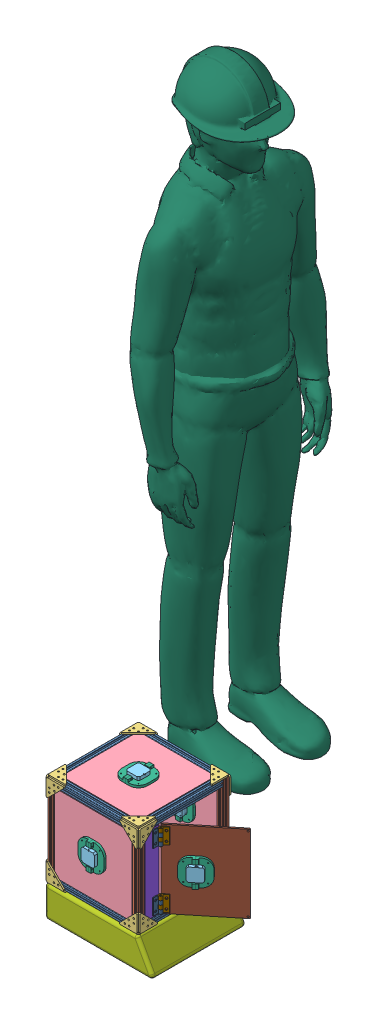
SolidWorks assembly boxOfDreams, configuration Default. Lengths in mm.
Overall size (790.39 1899.73 1088.72).
82 component instances, 15 part files, 239 mates.
Components (placement in the parent):
- 2020alu-1: 2020alu [Default] at origin size (20 20 250)
- 2020alu-2: 2020alu [Default] at (10 0 260) x (0 0 1) z (1 0 0) size (20 20 250)
- 2020alu-3: 2020alu [Default] at (270 0 0) size (20 20 250)
- 2020alu-4: 2020alu [Default] at (10 0 -10) x (0 0 -1) z (1 0 0) size (20 20 250)
- 2020alu_290-1: 2020alu_290 [Default] at (0 280 260) x (1 0 0) z (0 -1 0) size (20 20 290)
- 2020alu_290-2: 2020alu_290 [Default] at (270 280 260) x (0 0 1) z (0 -1 0) size (20 20 290)
- 2020alu_290-3: 2020alu_290 [Default] at (270 280 -10) x (1 0 0) z (0 -1 0) size (20 20 290)
- 2020alu_290-4: 2020alu_290 [Default] at (0 -10 -10) x (0 0 1) z (0 1 0) size (20 20 290)
- 2020alu-6: 2020alu [Default] at (260 270 260) x (0 0 1) z (-1 0 0) size (20 20 250)
- 2020alu-7: 2020alu [Default] at (270 270 0) size (20 20 250)
- 2020alu-8: 2020alu [Default] at (10 270 -10) x (0 0 -1) z (1 0 0) size (20 20 250)
- 2020alu-9: 2020alu [Default] at (0 270 0) size (20 20 250)
- bracket-2: bracket [Default] at (20 250 -20) x (-1 0 0) z (0 0 -1) size (55.76 55.76 5)
- bracket-3: bracket [Default] at (-15 250 10) x (0 0 -1) z (1 0 0) size (55.76 55.76 5)
- bracket-4: bracket [Default] at (20 285 10) x (-1 0 0) z (0 -1 0) size (55.76 55.76 5)
- bracket-5: bracket [Default] at (250 250 -25) size (55.76 55.76 5)
- bracket-7: bracket [Default] at (250 280 10) x (1 0 0) z (0 1 0) size (55.76 55.76 5)
- bracket-8: bracket [Default] at (250 20 -25) x (0 -1 0) z (0 0 1) size (55.76 55.76 5)
- bracket-10: bracket [Default] at (20 20 -20) x (0 -1 0) z (0 0 -1) size (55.76 55.76 5)
- glassPlex-2: glassPlex [Default] at (135.0355 135.0355 -20) size (247 247 5)
- bracket-11: bracket [Default] at (20 285 240) x (0 0 1) z (0 -1 0) size (55.76 55.76 5)
- bracket-12: bracket [Default] at (250 280 240) x (0 0 1) z (0 1 0) size (55.76 55.76 5)
- bracket-13: bracket [Default] at (20 250 275) x (-1 0 0) z (0 0 -1) size (55.76 55.76 5)
- glassPlex-3: glassPlex [Default] at (135.0355 280 124.9645) x (1 0 0) z (0 -1 0) size (247 247 5)
- bracket-14: bracket [Default] at (250 250 270) size (55.76 55.76 5)
- bracket-15: bracket [Default] at (250 20 270) x (0 -1 0) z (0 0 1) size (55.76 55.76 5)
- bracket-16: bracket [Default] at (20 20 270) x (-1 0 0) z (0 0 1) size (55.76 55.76 5)
- glassPlex-4: glassPlex [Default] at (134.9645 135.0355 265) size (247 247 5)
- bracket-17: bracket [Default] at (-10 250 240) x (0 0 1) z (-1 0 0) size (55.76 55.76 5)
- bracket-18: bracket [Default] at (-10 20 240) x (0 -1 0) z (-1 0 0) size (55.76 55.76 5)
- bracket-19: bracket [Default] at (-10 20 10) x (0 0 -1) z (-1 0 0) size (55.76 55.76 5)
- glassPlex-5: glassPlex [Default] at (-10 135.0355 125.0355) x (0 0 -1) z (1 0 0) size (247 247 5)
- bracket-22: bracket [Default] at (250 -15 10) x (1 0 0) z (0 1 0) size (55.76 55.76 5)
- bracket-23: bracket [Default] at (250 -10 240) x (1 0 0) z (0 -1 0) size (55.76 55.76 5)
- bracket-24: bracket [Default] at (20 -10 10) x (-1 0 0) z (0 -1 0) size (55.76 55.76 5)
- bracket-25: bracket [Default] at (20 -10 240) x (0 0 1) z (0 -1 0) size (55.76 55.76 5)
- glassPlex-6: glassPlex [Default] at (135.0355 -5 124.9645) x (1 0 0) z (0 -1 0) size (247 247 5)
- nema17-1: nema17 [Default] at (134.9645 135.0355 287) x (0 0 -1) z (1 0 0) size (77.9 47.49 42.3)
- nemaLock-1: nemaLock [Default] at (134.9645 135.0355 270) size (41.5 83 14.5)
- nemaLock-2: nemaLock [Default] at (134.9645 135.0355 270) x (-1 0 0) z (0 0 1) size (41.5 83 14.5)
- nemaLock-3: nemaLock [Default] at (134.9645 135.0355 265) x (1 0 0) z (0 0 -1) size (41.5 83 14.5)
- nemaLock-4: nemaLock [Default] at (134.9645 135.0355 265) x (-1 0 0) z (0 0 -1) size (41.5 83 14.5)
- nemaLock-5: nemaLock [Default] at (135.0355 -5 124.9645) x (0 0 -1) z (0 1 0) size (41.5 83 14.5)
- nemaLock-6: nemaLock [Default] at (135.0355 -5 124.9645) x (0 0 1) z (0 1 0) size (41.5 83 14.5)
- nemaLock-7: nemaLock [Default] at (135.0355 -10 124.9645) x (0 0 -1) z (0 -1 0) size (41.5 83 14.5)
- nemaLock-8: nemaLock [Default] at (135.0355 -10 124.9645) x (0 0 1) z (0 -1 0) size (41.5 83 14.5)
- nema17-2: nema17 [Default] at (135.0355 -27 124.9645) x (0 1 0) z (0 0 1) size (77.9 47.49 42.3)
- nemaLock-9: nemaLock [Default] at (135.0355 135.0355 -15) size (41.5 83 14.5)
- nemaLock-10: nemaLock [Default] at (135.0355 135.0355 -15) x (-1 0 0) z (0 0 1) size (41.5 83 14.5)
- nemaLock-11: nemaLock [Default] at (135.0355 135.0355 -20) x (-1 0 0) z (0 0 -1) size (41.5 83 14.5)
- nemaLock-12: nemaLock [Default] at (135.0355 135.0355 -20) x (1 0 0) z (0 0 -1) size (41.5 83 14.5)
- nema17-3: nema17 [Default] at (135.0355 135.0355 -37) x (0 0 1) z (-1 0 0) size (77.9 47.49 42.3)
- nemaLock-13: nemaLock [Default] at (135.0355 275 124.9645) x (-1 0 0) z (0 -1 0) size (41.5 83 14.5)
- nemaLock-14: nemaLock [Default] at (135.0355 275 124.9645) x (1 0 0) z (0 -1 0) size (41.5 83 14.5)
- nemaLock-15: nemaLock [Default] at (135.0355 280 124.9645) x (1 0 0) z (0 1 0) size (41.5 83 14.5)
- nemaLock-16: nemaLock [Default] at (135.0355 280 124.9645) x (-1 0 0) z (0 1 0) size (41.5 83 14.5)
- nema17-4: nema17 [Default] at (135.0355 297 124.9645) x (0 -1 0) z (0 0 1) size (77.9 47.49 42.3)
- nemaLock-17: nemaLock [Default] at (-5 135.0355 125.0355) x (0 0 -1) z (1 0 0) size (41.5 83 14.5)
- nemaLock-18: nemaLock [Default] at (-5 135.0355 125.0355) x (0 0 1) z (1 0 0) size (41.5 83 14.5)
- nemaLock-19: nemaLock [Default] at (-10 135.0355 125.0355) x (0 0 1) z (-1 0 0) size (41.5 83 14.5)
- nemaLock-20: nemaLock [Default] at (-10 135.0355 125.0355) x (0 0 -1) z (-1 0 0) size (41.5 83 14.5)
- nema17-5: nema17 [Default] at (-27 135.0355 125.0355) size (77.9 47.49 42.3)
- plateu-1: plateu [Default] at (160 -115 125) x (0 0 -1) z (0 1 0) size (300 343.09 100)
- bracket-26: bracket [Default] at (285 250 240) x (0 0 1) z (-1 0 0) size (55.76 55.76 5)
- bracket-27: bracket [Default] at (285 20 240) x (0 -1 0) z (-1 0 0) size (55.76 55.76 5)
- glassPlex_door1-1: glassPlex_door1 [Default] at (280 135.0355 125.0355) x (0 0 1) z (-1 0 0) size (43.5 247 5)
- Hinge A-1: Hinge A [Default] at (290.1769 228.5355 194.144) x (0.775881 0 -0.63088) z (0.63088 0 0.775881) size (26.5 50 11)
- Hinge B-1: Hinge B [Default] at (280 228.5355 215.5355) x (0 0 -1) z (1 0 0) size (26.5 50 11)
- Hinge A-2: Hinge A [Default] at (290.1769 41.5355 194.144) x (0.775881 0 -0.63088) z (0.63088 0 0.775881) size (26.5 50 11)
- Hinge B-2: Hinge B [Default] at (280 41.5355 215.5355) x (0 0 -1) z (1 0 0) size (26.5 50 11)
- glassPlex_door2-1: glassPlex_door2 [Default] at (344.1006 135.0355 150.2978) x (-0.775881 0 0.63088) z (-0.63088 0 -0.775881) size (203.5 247 5)
- nemaLock-21: nemaLock [Default] at (344.1006 135.0355 150.2978) x (0.775881 0 -0.63088) z (0.63088 0 0.775881) size (41.5 83 14.5)
- nemaLock-22: nemaLock [Default] at (344.1006 135.0355 150.2978) x (-0.775881 0 0.63088) z (0.63088 0 0.775881) size (41.5 83 14.5)
- nemaLock-23: nemaLock [Default] at (340.9462 135.0355 146.4184) x (-0.775881 0 0.63088) z (-0.63088 0 -0.775881) size (41.5 83 14.5)
- nemaLock-24: nemaLock [Default] at (340.9462 135.0355 146.4184) x (0.775881 0 -0.63088) z (-0.63088 0 -0.775881) size (41.5 83 14.5)
- nema17-6: nema17 [Default] at (354.8256 135.0355 163.4878) x (-0.63088 0 -0.775881) z (0.775881 0 -0.63088) size (77.9 47.49 42.3)
- camBracket-1: camBracket [Default] at (30.4289 265 20.4289) x (0.707107 0 -0.707107) z (0 1 0) size (77.78 38.89 10)
- Omnivision OV2710 CMOS CCTV Wide Angle USB Camera-1: Omnivision OV2710 CMOS CCTV Wide Angle USB Camera [Default] at (26.9289 260.0503 16.9289) x (-0.5 -0.707107 -0.5) z (-0.707107 0 0.707107) size (38 28 38)
- camBracket-2: camBracket [Default] at (239.5711 5 229.5711) x (0.707107 0 -0.707107) z (0 -1 0) size (77.78 38.89 10)
- Omnivision OV2710 CMOS CCTV Wide Angle USB Camera-2: Omnivision OV2710 CMOS CCTV Wide Angle USB Camera [Default] at (243.0711 9.9497 233.0711) x (0.5 0.707107 0.5) z (-0.707107 0 0.707107) size (38 28 38)
- rubik-1: rubik [Default] at (107 107 153) size (56 56 56)
- Worker Man WITH Yellow Hardhat-2: Worker Man WITH Yellow Hardhat [Default] at (0 -100 -216.7492) x (-1 0 0) z (0 0 -1) size (348.25 1883.85 575.19)
Mates (geometry in assembly coordinates):
- Coincident1: coincident aligned: plane of 2020alu-1 through (0 0 0) normal (0 0 1)
- Coincident2: coincident aligned: plane of 2020alu-1 through (0 0 0) normal (0 1 0)
- Coincident3: coincident aligned: plane of 2020alu-1 through (0 0 0) normal (1 0 0)
- Coincident6: coincident anti-aligned: plane of 2020alu-2 through (10 0 260) normal (0 -1 0)
- Coincident7: coincident aligned: line of 2020alu-1 through (10 3.5 250) axis (0 1 0); line of 2020alu-2 through (10 3.5 250) axis (0 1 0)
- Perpendicular2: perpendicular: plane of 2020alu-1 through (10 8.5 250) normal (1 0 0); plane of 2020alu-2 through (260 8.5 250) normal (0 0 -1)
- Coincident9: coincident anti-aligned: line of 2020alu-2 through (260 3.5 250) axis (0 1 0); line of 2020alu-3 through (260 8.5 250) axis (0 -1 0)
- Perpendicular3: perpendicular: plane of 2020alu-2 through (260 8.5 250) normal (0 0 -1); plane of 2020alu-3 through (260 8.5 250) normal (-1 0 0)
- Coincident11: coincident aligned: plane of 2020alu-3 through (270 0 0) normal (0 1 0)
- Coincident12: coincident aligned: plane of 2020alu-4 through (10 0 -10) normal (0 1 0)
- Coincident13: coincident aligned: line of 2020alu-3 through (5 260 8.5) axis (0 0 -1); line of 2020alu-4 through (260 8.5 0) axis (0 -1 0)
- Perpendicular4: perpendicular: plane of 2020alu-3 through (260 8.5 250) normal (-1 0 0); plane of 2020alu-4 through (260 8.5 0) normal (0 0 1)
- Coincident15: coincident anti-aligned: plane of 2020alu-1 through (-4 -7.182 250) normal (0 0 1); plane of 2020alu_290-1 through (-3.6 -10 250) normal (0 0 -1)
- Coincident16: coincident anti-aligned: plane of 2020alu-2 through (10 7.182 256) normal (-1 0 0); plane of 2020alu_290-1 through (10 -10 251.5) normal (1 0 0)
- Coincident17: coincident aligned: line of 2020alu-1 through (-8.5 -10 250) axis (1 0 0); line of 2020alu_290-1 through (-8.5 -10 250) axis (1 0 0)
- Coincident18: coincident anti-aligned: plane of 2020alu-2 through (260 7.182 256) normal (1 0 0); plane of 2020alu_290-2 through (260 -10 256.4) normal (-1 0 0)
- Coincident19: coincident anti-aligned: plane of 2020alu-3 through (266 -7.182 250) normal (0 0 1); plane of 2020alu_290-2 through (278.5 -10 250) normal (0 0 -1)
- Coincident20: coincident aligned: line of 2020alu-3 through (273.6 -10 250) axis (1 0 0); line of 2020alu_290-2 through (273.5 -10 250) axis (1 0 0)
- Coincident21: coincident anti-aligned: plane of 2020alu-3 through (266 -7.182 0) normal (0 0 -1); plane of 2020alu_290-3 through (278.5 -10 0) normal (0 0 1)
- Coincident22: coincident anti-aligned: plane of 2020alu-4 through (260 -7.182 -6) normal (1 0 0); plane of 2020alu_290-3 through (260 -10 -18.5) normal (-1 0 0)
- Coincident23: coincident anti-aligned: line of 2020alu-3 through (4.9 261.5 -10) axis (0 1 0); line of 2020alu_290-3 through (4.9 266.4 -10) axis (0 -1 0)
- Coincident24: coincident anti-aligned: plane of 2020alu-4 through (10 -7.182 -6) normal (-1 0 0); plane of 2020alu_290-4 through (10 280 -13.6) normal (1 0 0)
- Coincident25: coincident anti-aligned: plane of 2020alu-1 through (-4 -7.182 0) normal (0 0 -1); plane of 2020alu_290-4 through (8.5 280 0) normal (0 0 1)
- Coincident26: coincident aligned: line of 2020alu-4 through (10 -10 -1.5) axis (0 0 -1); line of 2020alu_290-4 through (10 -10 -1.5) axis (0 0 -1)
- Coincident35: coincident aligned: line of 2020alu-6 through (260 278.5 250) axis (0 -1 0); line of 2020alu-7 through (260 278.5 250) axis (0 -1 0)
- Perpendicular6: perpendicular: plane of 2020alu-6 through (10 278.5 250) normal (0 0 -1); plane of 2020alu-7 through (260 278.5 250) normal (-1 0 0)
- Coincident40: coincident anti-aligned: line of 2020alu_290-4 through (10 280 -1.5) axis (0 0 -1); line of 2020alu-8 through (10 280 -6.4) axis (0 0 1)
- Coincident43: coincident anti-aligned: line of 2020alu_290-3 through (260 280 -13.5) axis (0 0 -1); line of 2020alu-8 through (260 280 -18.5) axis (0 0 1)
- Coincident44: coincident anti-aligned: line of 2020alu_290-4 through (10 280 -13.6) axis (0 0 -1); line of 2020alu-8 through (10 280 -18.5) axis (0 0 1)
- Coincident45: coincident: plane of 2020alu_290-4 through (8.5 280 -20) normal (0 0 -1); line of 2020alu-8 through (10 273.5 -20) axis (0 1 0)
- Coincident46: coincident anti-aligned: line of 2020alu_290-1 through (3.6 280 250) axis (1 0 0); line of 2020alu-9 through (8.5 280 250) axis (-1 0 0)
- Coincident47: coincident anti-aligned: line of 2020alu_290-4 through (5 3.5 280) axis (0 1 0); line of 2020alu-9 through (4.9 8.5 280) axis (0 -1 0)
- Coincident48: coincident: plane of 2020alu_290-4 through (-10 280 -1.5) normal (-1 0 0); line of 2020alu-9 through (5 -10 278.5) axis (0 0 -1)
- Coincident51: coincident anti-aligned: plane of 2020alu_290-4 through (8.5 280 -20) normal (0 0 -1); plane of bracket-2 through (-5 275 -20) normal (0 0 1)
- Coincident52: coincident aligned: line of bracket-2 through (-10 227.2426 -20) axis (0 1 0); line of bracket-3 through (-10 227.2426 -20) axis (0 1 0)
- Coincident53: coincident anti-aligned: plane of 2020alu-9 through (-10 278.5 250) normal (-1 0 0); plane of bracket-3 through (-10 275 -15) normal (1 0 0)
- Coincident54: coincident aligned: plane of 2020alu-9 through (-3.6 280 250) normal (0 1 0); plane of bracket-3 through (-10 280 32.7574) normal (0 1 0)
- Coincident55: coincident anti-aligned: line of bracket-3 through (-10 280 -15) axis (0 0 1); line of bracket-4 through (-10 280 32.7574) axis (0 0 -1)
- Coincident56: coincident aligned: line of bracket-2 through (-5 280 -20) axis (1 0 0); line of bracket-4 through (-5 280 -20) axis (1 0 0)
- Coincident57: coincident aligned: plane of 2020alu_290-3 through (280 -10 -18.5) normal (1 0 0); plane of bracket-5 through (280 275 -20) normal (1 0 0)
- Coincident58: coincident aligned: plane of 2020alu-8 through (260 280 -18.5) normal (0 1 0); plane of bracket-5 through (227.2426 280 -20) normal (0 1 0)
- Coincident59: coincident anti-aligned: plane of 2020alu_290-3 through (266.4 -10 -20) normal (0 0 -1); plane of bracket-5 through (275 275 -20) normal (0 0 1)
- Coincident64: coincident aligned: line of bracket-5 through (275 280 -20) axis (-1 0 0); line of bracket-7 through (275 280 -20) axis (-1 0 0)
- Coincident65: coincident aligned: plane of 2020alu-4 through (260 -10 -18.5) normal (0 -1 0); plane of bracket-8 through (275 -10 -20) normal (0 -1 0)
- Coincident66: coincident aligned: plane of 2020alu_290-3 through (280 -10 -18.5) normal (1 0 0); plane of bracket-8 through (280 42.7574 -20) normal (1 0 0)
- Coincident67: coincident anti-aligned: plane of 2020alu_290-3 through (266.4 -10 -20) normal (0 0 -1); plane of bracket-8 through (275 -5 -20) normal (0 0 1)
- Coincident71: coincident anti-aligned: plane of 2020alu_290-2 through (261.5 -10 250) normal (0 0 -1); plane of 2020alu-7 through (266 262.818 250) normal (0 0 1)
- Coincident72: coincident aligned: line of 2020alu_290-2 through (260 280 268.5) axis (0 0 -1); line of 2020alu-6 through (260 280 268.5) axis (0 0 -1)
- Coincident73: coincident anti-aligned: line of 2020alu_290-2 through (261.5 280 250) axis (1 0 0); line of 2020alu-7 through (266.4 280 250) axis (-1 0 0)
- Coincident74: coincident aligned: plane of 2020alu_290-4 through (-10 280 -13.6) normal (-1 0 0); plane of bracket-10 through (-10 42.7574 -25) normal (-1 0 0)
- Coincident75: coincident aligned: plane of 2020alu-4 through (260 -10 -18.5) normal (0 -1 0); plane of bracket-10 through (-5 -10 -25) normal (0 -1 0)
- Coincident76: coincident anti-aligned: plane of 2020alu_290-4 through (8.5 280 -20) normal (0 0 -1); plane of bracket-10 through (-5 -5 -20) normal (0 0 1)
- Coincident77: coincident anti-aligned: plane of bracket-2 through (-5 275 -20) normal (0 0 1); plane of glassPlex-2 through (13.5355 13.5355 -20) normal (0 0 -1)
- Concentric4: concentric aligned: cylinder of bracket-5 through (253.5355 253.5355 -20) axis (0 0 -1) radius 2.5; cylinder of glassPlex-2 through (253.5355 253.5355 -15) axis (0 0 -1) radius 2.5
- Parallel5: parallel anti-aligned: plane of 2020alu_290-4 through (10 280 -13.6) normal (1 0 0); plane of glassPlex-2 through (11.5355 256.5355 -15) normal (-1 0 0)
- Coincident79: coincident aligned: plane of 2020alu-9 through (-10 278.5 250) normal (-1 0 0); plane of bracket-11 through (-10 280 217.2426) normal (-1 0 0)
- Coincident80: coincident aligned: plane of 2020alu-6 through (10 278.5 270) normal (0 0 1); plane of bracket-11 through (-5 280 270) normal (0 0 1)
- Coincident81: coincident anti-aligned: plane of 2020alu-6 through (10 280 268.5) normal (0 1 0); plane of bracket-11 through (-5 280 265) normal (0 -1 0)
- Coincident84: coincident aligned: plane of 2020alu-7 through (280 278.5 250) normal (1 0 0); plane of bracket-12 through (280 285 217.2426) normal (1 0 0)
- Coincident85: coincident aligned: plane of 2020alu-6 through (10 278.5 270) normal (0 0 1); plane of bracket-12 through (275 285 270) normal (0 0 1)
- Coincident86: coincident anti-aligned: plane of 2020alu-6 through (10 280 256.4) normal (0 1 0); plane of bracket-12 through (275 280 265) normal (0 -1 0)
- Coincident87: coincident aligned: plane of 2020alu_290-1 through (-10 -10 268.5) normal (-1 0 0); plane of bracket-13 through (-10 275 270) normal (-1 0 0)
- Coincident88: coincident aligned: plane of 2020alu-6 through (10 280 268.5) normal (0 1 0); plane of bracket-13 through (42.7574 280 270) normal (0 1 0)
- Coincident89: coincident anti-aligned: plane of 2020alu-6 through (10 261.5 270) normal (0 0 1); plane of bracket-13 through (-5 275 270) normal (0 0 -1)
- Coincident90: coincident anti-aligned: plane of bracket-12 through (275 280 265) normal (0 -1 0); plane of glassPlex-3 through (13.5355 280 3.4645) normal (0 1 0)
- Concentric7: concentric anti-aligned: cylinder of bracket-7 through (253.5355 285 6.4645) axis (0 -1 0) radius 2.5; cylinder of glassPlex-3 through (253.5355 275 6.4645) axis (0 1 0) radius 2.5
- Parallel6: parallel anti-aligned: plane of 2020alu-6 through (10 278.5 250) normal (0 0 -1); plane of glassPlex-3 through (256.5355 275 248.4645) normal (0 0 1)
- Coincident92: coincident aligned: plane of 2020alu_290-2 through (280 -10 268.5) normal (1 0 0); plane of bracket-14 through (280 275 275) normal (1 0 0)
- Coincident93: coincident aligned: plane of 2020alu-6 through (10 280 268.5) normal (0 1 0); plane of bracket-14 through (227.2426 280 275) normal (0 1 0)
- Coincident94: coincident anti-aligned: plane of 2020alu_290-2 through (278.5 -10 270) normal (0 0 1); plane of bracket-14 through (275 275 270) normal (0 0 -1)
- Coincident95: coincident anti-aligned: plane of 2020alu_290-2 through (261.5 -10 270) normal (0 0 1); plane of bracket-15 through (275 -5 270) normal (0 0 -1)
- Coincident96: coincident aligned: plane of 2020alu_290-2 through (280 -10 268.5) normal (1 0 0); plane of bracket-15 through (280 42.7574 275) normal (1 0 0)
- Coincident97: coincident aligned: plane of 2020alu-2 through (260 -10 268.5) normal (0 -1 0); plane of bracket-15 through (275 -10 275) normal (0 -1 0)
- Coincident98: coincident anti-aligned: plane of 2020alu_290-1 through (8.5 -10 270) normal (0 0 1); plane of bracket-16 through (-5 -5 270) normal (0 0 -1)
- Coincident99: coincident aligned: plane of 2020alu_290-1 through (-10 -10 268.5) normal (-1 0 0); plane of bracket-16 through (-10 -5 275) normal (-1 0 0)
- Coincident100: coincident aligned: plane of 2020alu-2 through (260 -10 268.5) normal (0 -1 0); plane of bracket-16 through (42.7574 -10 275) normal (0 -1 0)
- Coincident101: coincident anti-aligned: plane of bracket-13 through (-5 275 270) normal (0 0 -1); plane of glassPlex-4 through (13.4645 13.5355 270) normal (0 0 1)
- Concentric8: concentric anti-aligned: cylinder of bracket-13 through (16.4645 253.5355 270) axis (0 0 1) radius 2.5; cylinder of glassPlex-4 through (16.4645 253.5355 270) axis (0 0 -1) radius 2.5
- Parallel7: parallel anti-aligned: plane of 2020alu_290-2 through (260 -10 268.5) normal (-1 0 0); plane of glassPlex-4 through (258.4645 13.5355 270) normal (1 0 0)
- Coincident103: coincident aligned: plane of 2020alu-7 through (280 278.5 250) normal (1 0 0); plane of bracket-7 through (280 285 -15) normal (1 0 0)
- Coincident104: coincident anti-aligned: plane of 2020alu_290-1 through (-10 -10 251.5) normal (-1 0 0); plane of bracket-17 through (-10 275 265) normal (1 0 0)
- Coincident105: coincident aligned: plane of 2020alu_290-1 through (-3.6 -10 270) normal (0 0 1); plane of bracket-17 through (-15 275 270) normal (0 0 1)
- Coincident106: coincident aligned: plane of 2020alu-9 through (-3.6 280 250) normal (0 1 0); plane of bracket-17 through (-15 280 217.2426) normal (0 1 0)
- Coincident107: coincident anti-aligned: plane of 2020alu_290-1 through (-10 -10 251.5) normal (-1 0 0); plane of bracket-18 through (-10 -5 265) normal (1 0 0)
- Coincident108: coincident aligned: plane of 2020alu_290-1 through (-3.6 -10 270) normal (0 0 1); plane of bracket-18 through (-15 42.7574 270) normal (0 0 1)
- Coincident109: coincident aligned: plane of 2020alu-1 through (-3.6 -10 250) normal (0 -1 0); plane of bracket-18 through (-15 -10 265) normal (0 -1 0)
- Coincident110: coincident anti-aligned: plane of 2020alu_290-4 through (-10 280 -1.5) normal (-1 0 0); plane of bracket-19 through (-10 -5 -15) normal (1 0 0)
- Coincident111: coincident aligned: plane of 2020alu_290-4 through (-8.5 280 -20) normal (0 0 -1); plane of bracket-19 through (-15 -5 -20) normal (0 0 -1)
- Coincident112: coincident aligned: plane of 2020alu-1 through (-3.6 -10 250) normal (0 -1 0); plane of bracket-19 through (-15 -10 32.7574) normal (0 -1 0)
- Coincident113: coincident anti-aligned: plane of bracket-3 through (-10 275 -15) normal (1 0 0); plane of glassPlex-5 through (-10 13.5355 246.5355) normal (-1 0 0)
- Concentric9: concentric anti-aligned: cylinder of bracket-17 through (-15 253.5355 243.5355) axis (1 0 0) radius 2.5; cylinder of glassPlex-5 through (-5 253.5355 243.5355) axis (-1 0 0) radius 2.5
- Parallel8: parallel anti-aligned: plane of 2020alu_290-4 through (-8.5 280 0) normal (0 0 1); plane of glassPlex-5 through (-5 13.5355 1.5355) normal (0 0 -1)
- Coincident124: coincident anti-aligned: plane of 2020alu-4 through (260 -10 -6.4) normal (0 -1 0); plane of bracket-22 through (275 -10 -15) normal (0 1 0)
- Coincident125: coincident aligned: plane of 2020alu-4 through (260 -8.5 -20) normal (0 0 -1); plane of bracket-22 through (227.2426 -10 -20) normal (0 0 -1)
- Coincident126: coincident aligned: plane of 2020alu-3 through (280 -8.5 250) normal (1 0 0); plane of bracket-22 through (280 -10 -15) normal (1 0 0)
- Coincident127: coincident anti-aligned: plane of 2020alu-3 through (278.5 -10 250) normal (0 -1 0); plane of bracket-23 through (275 -10 265) normal (0 1 0)
- Coincident128: coincident aligned: plane of 2020alu-2 through (260 -8.5 270) normal (0 0 1); plane of bracket-23 through (227.2426 -15 270) normal (0 0 1)
- Coincident129: coincident aligned: plane of 2020alu-3 through (280 -8.5 250) normal (1 0 0); plane of bracket-23 through (280 -15 265) normal (1 0 0)
- Coincident130: coincident anti-aligned: plane of 2020alu-4 through (260 -10 -18.5) normal (0 -1 0); plane of bracket-24 through (-5 -10 -15) normal (0 1 0)
- Coincident131: coincident aligned: plane of 2020alu-4 through (260 -8.5 -20) normal (0 0 -1); plane of bracket-24 through (42.7574 -15 -20) normal (0 0 -1)
- Coincident132: coincident aligned: plane of 2020alu-1 through (-10 -8.5 250) normal (-1 0 0); plane of bracket-24 through (-10 -15 -15) normal (-1 0 0)
- Coincident133: coincident anti-aligned: plane of 2020alu-1 through (8.5 -10 250) normal (0 -1 0); plane of bracket-25 through (-5 -10 265) normal (0 1 0)
- Coincident134: coincident aligned: plane of 2020alu-2 through (260 -8.5 270) normal (0 0 1); plane of bracket-25 through (-5 -15 270) normal (0 0 1)
- Coincident135: coincident aligned: plane of 2020alu-1 through (-10 -8.5 250) normal (-1 0 0); plane of bracket-25 through (-10 -15 217.2426) normal (-1 0 0)
- Coincident136: coincident anti-aligned: plane of bracket-22 through (275 -10 -15) normal (0 1 0); plane of glassPlex-6 through (13.5355 -10 3.4645) normal (0 -1 0)
- Concentric10: concentric anti-aligned: cylinder of bracket-22 through (253.5355 -10 6.4645) axis (0 -1 0) radius 2.5; cylinder of glassPlex-6 through (253.5355 -10 6.4645) axis (0 1 0) radius 2.5
- Parallel10: parallel anti-aligned: plane of 2020alu-2 through (260 -8.5 250) normal (0 0 -1); plane of glassPlex-6 through (256.5355 -10 248.4645) normal (0 0 1)
- Coincident145: coincident anti-aligned: plane of glassPlex-4 through (13.4645 13.5355 270) normal (0 0 1); plane of nemaLock-1 through (134.9645 135.0355 270) normal (0 0 -1)
- Concentric11: concentric anti-aligned: cylinder of glassPlex-4 through (163.2487 106.7513 270) axis (0 0 -1) radius 1.5; cylinder of nemaLock-1 through (163.2487 106.7513 269.5) axis (0 0 1) radius 1.5
- Concentric12: concentric anti-aligned: cylinder of glassPlex-4 through (163.2487 163.3198 270) axis (0 0 -1) radius 1.5; cylinder of nemaLock-1 through (163.2487 163.3198 269.5) axis (0 0 1) radius 1.5
- Coincident146: coincident anti-aligned: plane of nema17-1 through (134.9645 135.0355 277) normal (0 0 -1); plane of nemaLock-1 through (134.9645 135.0355 277) normal (0 0 1)
- Distance11: distance = 0.5 mm anti-aligned: plane of nema17-1 through (155.9645 124.0355 253) normal (1 0 0); plane of nemaLock-1 through (156.4645 135.0355 277) normal (-1 0 0)
- Distance12: distance = 0.5 mm anti-aligned: plane of nema17-1 through (145.9645 156.0355 253) normal (0 1 0); plane of nemaLock-1 through (134.9645 156.5355 277) normal (0 -1 0)
- Coincident149: coincident anti-aligned: plane of glassPlex-4 through (13.4645 13.5355 270) normal (0 0 1); plane of nemaLock-2 through (134.9645 135.0355 270) normal (0 0 -1)
- Concentric13: concentric anti-aligned: cylinder of glassPlex-4 through (106.6802 163.3198 270) axis (0 0 -1) radius 1.5; cylinder of nemaLock-2 through (106.6802 163.3198 269.5) axis (0 0 1) radius 1.5
- Concentric14: concentric anti-aligned: cylinder of glassPlex-4 through (106.6802 106.7513 270) axis (0 0 -1) radius 1.5; cylinder of nemaLock-2 through (106.6802 106.7513 269.5) axis (0 0 1) radius 1.5
- Coincident150: coincident anti-aligned: plane of glassPlex-4 through (13.4645 13.5355 265) normal (0 0 -1); plane of nemaLock-3 through (134.9645 135.0355 265) normal (0 0 1)
- Concentric15: concentric anti-aligned: cylinder of nemaLock-1 through (163.2487 163.3198 269.5) axis (0 0 1) radius 1.5; cylinder of nemaLock-3 through (163.2487 163.3198 265.5) axis (0 0 -1) radius 1.5
- Concentric16: concentric anti-aligned: cylinder of nemaLock-1 through (163.2487 106.7513 269.5) axis (0 0 1) radius 1.5; cylinder of nemaLock-3 through (163.2487 106.7513 265.5) axis (0 0 -1) radius 1.5
- Coincident151: coincident anti-aligned: plane of glassPlex-4 through (13.4645 13.5355 265) normal (0 0 -1); plane of nemaLock-4 through (134.9645 135.0355 265) normal (0 0 1)
- Concentric17: concentric anti-aligned: cylinder of nemaLock-3 through (134.9645 166.5355 254) axis (1 0 0) radius 1.5; cylinder of nemaLock-4 through (134.9645 166.5355 254) axis (-1 0 0) radius 1.5
- Coincident152: coincident anti-aligned: plane of nemaLock-3 through (134.9645 135.0355 258) normal (-1 0 0); plane of nemaLock-4 through (134.9645 135.0355 258) normal (1 0 0)
- Coincident153: coincident anti-aligned: plane of glassPlex-6 through (13.5355 -5 3.4645) normal (0 1 0); plane of nemaLock-5 through (135.0355 -5 124.9645) normal (0 -1 0)
- Concentric18: concentric aligned: cylinder of glassPlex-6 through (163.3198 -10 96.6802) axis (0 1 0) radius 1.5; cylinder of nemaLock-5 through (163.3198 -5.5 96.6802) axis (0 1 0) radius 1.5
- Concentric19: concentric aligned: cylinder of glassPlex-6 through (106.7513 -10 96.6802) axis (0 1 0) radius 1.5; cylinder of nemaLock-5 through (106.7513 -5.5 96.6802) axis (0 1 0) radius 1.5
- Coincident154: coincident anti-aligned: plane of glassPlex-6 through (13.5355 -5 3.4645) normal (0 1 0); plane of nemaLock-6 through (135.0355 -5 124.9645) normal (0 -1 0)
- Coincident155: coincident anti-aligned: plane of nemaLock-5 through (135.0355 2 124.9645) normal (0 0 1); plane of nemaLock-6 through (135.0355 2 124.9645) normal (0 0 -1)
- Concentric20: concentric aligned: cylinder of glassPlex-6 through (106.7513 -10 153.2487) axis (0 1 0) radius 1.5; cylinder of nemaLock-6 through (106.7513 -5.5 153.2487) axis (0 1 0) radius 1.5
- Coincident156: coincident anti-aligned: plane of glassPlex-6 through (13.5355 -10 3.4645) normal (0 -1 0); plane of nemaLock-7 through (135.0355 -10 124.9645) normal (0 1 0)
- Concentric21: concentric anti-aligned: cylinder of nemaLock-5 through (163.3198 -5.5 96.6802) axis (0 1 0) radius 1.5; cylinder of nemaLock-7 through (163.3198 -9.5 96.6802) axis (0 -1 0) radius 1.5
- Concentric22: concentric anti-aligned: cylinder of nemaLock-5 through (106.7513 -5.5 96.6802) axis (0 1 0) radius 1.5; cylinder of nemaLock-7 through (106.7513 -9.5 96.6802) axis (0 -1 0) radius 1.5
- Coincident157: coincident anti-aligned: plane of glassPlex-6 through (13.5355 -10 3.4645) normal (0 -1 0); plane of nemaLock-8 through (135.0355 -10 124.9645) normal (0 1 0)
- Coincident158: coincident anti-aligned: plane of nemaLock-7 through (135.0355 -17 124.9645) normal (0 0 1); plane of nemaLock-8 through (135.0355 -17 124.9645) normal (0 0 -1)
- Concentric23: concentric anti-aligned: cylinder of nemaLock-7 through (166.5355 -21 124.9645) axis (0 0 -1) radius 1.5; cylinder of nemaLock-8 through (166.5355 -21 124.9645) axis (0 0 1) radius 1.5
- Coincident159: coincident anti-aligned: plane of nemaLock-7 through (135.0355 -17 124.9645) normal (0 -1 0); plane of nema17-2 through (135.0355 -17 124.9645) normal (0 1 0)
- Distance13: distance = 0.5 mm anti-aligned: plane of nema17-2 through (146.0355 7 103.9645) normal (0 0 -1); plane of nemaLock-7 through (135.0355 -17 103.4645) normal (0 0 1)
- Distance14: distance = 0.5 mm anti-aligned: plane of nema17-2 through (156.0355 7 135.9645) normal (1 0 0); plane of nemaLock-7 through (156.5355 -17 124.9645) normal (-1 0 0)
- Coincident162: coincident anti-aligned: plane of glassPlex-2 through (13.5355 13.5355 -15) normal (0 0 1); plane of nemaLock-9 through (135.0355 135.0355 -15) normal (0 0 -1)
- Concentric24: concentric anti-aligned: cylinder of glassPlex-2 through (163.3198 106.7513 -15) axis (0 0 -1) radius 1.5; cylinder of nemaLock-9 through (163.3198 106.7513 -15.5) axis (0 0 1) radius 1.5
- Concentric25: concentric anti-aligned: cylinder of glassPlex-2 through (163.3198 163.3198 -15) axis (0 0 -1) radius 1.5; cylinder of nemaLock-9 through (163.3198 163.3198 -15.5) axis (0 0 1) radius 1.5
- Coincident163: coincident anti-aligned: plane of glassPlex-2 through (13.5355 13.5355 -15) normal (0 0 1); plane of nemaLock-10 through (135.0355 135.0355 -15) normal (0 0 -1)
- Coincident164: coincident anti-aligned: plane of nemaLock-9 through (135.0355 135.0355 -8) normal (-1 0 0); plane of nemaLock-10 through (135.0355 135.0355 -8) normal (1 0 0)
- Concentric26: concentric anti-aligned: cylinder of nemaLock-9 through (135.0355 103.5355 -4) axis (1 0 0) radius 1.5; cylinder of nemaLock-10 through (135.0355 103.5355 -4) axis (-1 0 0) radius 1.5
- Coincident165: coincident anti-aligned: plane of glassPlex-2 through (13.5355 13.5355 -20) normal (0 0 -1); plane of nemaLock-11 through (135.0355 135.0355 -20) normal (0 0 1)
- Concentric27: concentric anti-aligned: circle of nemaLock-10; cylinder of nemaLock-11 through (106.7513 106.7513 -19.5) axis (0 0 -1) radius 1.5
- Concentric28: concentric anti-aligned: circle of nemaLock-10; circle of nemaLock-11
- Coincident168: coincident anti-aligned: plane of glassPlex-2 through (13.5355 13.5355 -20) normal (0 0 -1); plane of nemaLock-12 through (135.0355 135.0355 -20) normal (0 0 1)
- Concentric29: concentric anti-aligned: cylinder of nemaLock-11 through (135.0355 103.5355 -31) axis (-1 0 0) radius 1.5; cylinder of nemaLock-12 through (135.0355 103.5355 -31) axis (1 0 0) radius 1.5
- Coincident169: coincident anti-aligned: plane of nemaLock-11 through (135.0355 135.0355 -27) normal (1 0 0); plane of nemaLock-12 through (135.0355 135.0355 -27) normal (-1 0 0)
- Coincident170: coincident anti-aligned: plane of nemaLock-11 through (135.0355 135.0355 -27) normal (0 0 -1); plane of nema17-3 through (135.0355 135.0355 -27) normal (0 0 1)
- Distance15: distance = 0.5 mm anti-aligned: plane of nema17-3 through (156.0355 124.0355 -3) normal (1 0 0); plane of nemaLock-12 through (156.5355 135.0355 -27) normal (-1 0 0)
- Distance16: distance = 0.5 mm anti-aligned: plane of nemaLock-12 through (135.0355 113.5355 -27) normal (0 1 0); plane of nema17-3 through (124.0355 114.0355 -3) normal (0 -1 0)
- Coincident173: coincident anti-aligned: plane of glassPlex-3 through (13.5355 275 3.4645) normal (0 -1 0); plane of nemaLock-13 through (135.0355 275 124.9645) normal (0 1 0)
- Concentric30: concentric anti-aligned: cylinder of glassPlex-3 through (106.7513 275 153.2487) axis (0 1 0) radius 1.5; cylinder of nemaLock-13 through (106.7513 275.5 153.2487) axis (0 -1 0) radius 1.5
- Concentric31: concentric anti-aligned: cylinder of glassPlex-3 through (106.7513 275 96.6802) axis (0 1 0) radius 1.5; cylinder of nemaLock-13 through (106.7513 275.5 96.6802) axis (0 -1 0) radius 1.5
- Coincident174: coincident anti-aligned: plane of glassPlex-3 through (13.5355 275 3.4645) normal (0 -1 0); plane of nemaLock-14 through (135.0355 275 124.9645) normal (0 1 0)
- Concentric32: concentric anti-aligned: cylinder of nemaLock-13 through (135.0355 264 156.4645) axis (-1 0 0) radius 1.5; cylinder of nemaLock-14 through (135.0355 264 156.4645) axis (1 0 0) radius 1.5
- Coincident175: coincident anti-aligned: plane of nemaLock-13 through (135.0355 268 124.9645) normal (1 0 0); plane of nemaLock-14 through (135.0355 268 124.9645) normal (-1 0 0)
- Coincident176: coincident anti-aligned: plane of glassPlex-3 through (13.5355 280 3.4645) normal (0 1 0); plane of nemaLock-15 through (135.0355 280 124.9645) normal (0 -1 0)
- Concentric33: concentric anti-aligned: circle of nemaLock-14; cylinder of nemaLock-15 through (163.3198 279.5 153.2487) axis (0 1 0) radius 1.5
- Concentric34: concentric anti-aligned: circle of nemaLock-14; cylinder of nemaLock-15 through (163.3198 279.5 96.6802) axis (0 1 0) radius 1.5
- Coincident179: coincident anti-aligned: plane of glassPlex-3 through (13.5355 280 3.4645) normal (0 1 0); plane of nemaLock-16 through (135.0355 280 124.9645) normal (0 -1 0)
- Concentric35: concentric anti-aligned: cylinder of nemaLock-15 through (135.0355 291 156.4645) axis (1 0 0) radius 1.5; cylinder of nemaLock-16 through (135.0355 291 156.4645) axis (-1 0 0) radius 1.5
- Coincident180: coincident anti-aligned: plane of nemaLock-15 through (135.0355 287 124.9645) normal (-1 0 0); plane of nemaLock-16 through (135.0355 287 124.9645) normal (1 0 0)
- Coincident181: coincident anti-aligned: plane of nemaLock-16 through (135.0355 287 124.9645) normal (0 1 0); plane of nema17-4 through (135.0355 287 124.9645) normal (0 -1 0)
- Distance17: distance = 0.5 mm anti-aligned: plane of nema17-4 through (114.0355 263 135.9645) normal (-1 0 0); plane of nemaLock-16 through (113.5355 287 124.9645) normal (1 0 0)
- Distance18: distance = 0.5 mm anti-aligned: plane of nema17-4 through (124.0355 263 103.9645) normal (0 0 -1); plane of nemaLock-16 through (135.0355 287 103.4645) normal (0 0 1)
- Coincident184: coincident anti-aligned: plane of glassPlex-5 through (-5 13.5355 246.5355) normal (1 0 0); plane of nemaLock-17 through (-5 135.0355 125.0355) normal (-1 0 0)
- Concentric36: concentric anti-aligned: cylinder of glassPlex-5 through (-5 106.7513 96.7513) axis (-1 0 0) radius 1.5; cylinder of nemaLock-17 through (-5.5 106.7513 96.7513) axis (1 0 0) radius 1.5
- Concentric37: concentric anti-aligned: cylinder of glassPlex-5 through (-5 163.3198 96.7513) axis (-1 0 0) radius 1.5; cylinder of nemaLock-17 through (-5.5 163.3198 96.7513) axis (1 0 0) radius 1.5
- Coincident185: coincident anti-aligned: plane of glassPlex-5 through (-5 13.5355 246.5355) normal (1 0 0); plane of nemaLock-18 through (-5 135.0355 125.0355) normal (-1 0 0)
- Concentric38: concentric anti-aligned: cylinder of nemaLock-17 through (6 103.5355 125.0355) axis (0 0 -1) radius 1.5; cylinder of nemaLock-18 through (6 103.5355 125.0355) axis (0 0 1) radius 1.5
- Coincident186: coincident anti-aligned: plane of nemaLock-17 through (2 135.0355 125.0355) normal (0 0 1); plane of nemaLock-18 through (2 135.0355 125.0355) normal (0 0 -1)
- Coincident187: coincident anti-aligned: plane of glassPlex-5 through (-10 13.5355 246.5355) normal (-1 0 0); plane of nemaLock-19 through (-10 135.0355 125.0355) normal (1 0 0)
- Concentric39: concentric anti-aligned: circle of nemaLock-18; cylinder of nemaLock-19 through (-9.5 106.7513 153.3198) axis (-1 0 0) radius 1.5
- Concentric40: concentric anti-aligned: circle of nemaLock-18; cylinder of nemaLock-19 through (-9.5 163.3198 153.3198) axis (-1 0 0) radius 1.5
- Coincident190: coincident anti-aligned: plane of glassPlex-5 through (-10 13.5355 246.5355) normal (-1 0 0); plane of nemaLock-20 through (-10 135.0355 125.0355) normal (1 0 0)
- Concentric41: concentric anti-aligned: cylinder of nemaLock-19 through (-21 103.5355 125.0355) axis (0 0 1) radius 1.5; cylinder of nemaLock-20 through (-21 103.5355 125.0355) axis (0 0 -1) radius 1.5
- Coincident191: coincident anti-aligned: plane of nemaLock-19 through (-17 135.0355 125.0355) normal (0 0 -1); plane of nemaLock-20 through (-17 135.0355 125.0355) normal (0 0 1)
- Coincident192: coincident anti-aligned: plane of nemaLock-19 through (-17 135.0355 125.0355) normal (-1 0 0); plane of nema17-5 through (-17 135.0355 125.0355) normal (1 0 0)
- Distance19: distance = 0.5 mm anti-aligned: plane of nema17-5 through (7 156.0355 136.0355) normal (0 1 0); plane of nemaLock-19 through (-17 156.5355 125.0355) normal (0 -1 0)
- Distance20: distance = 0.5 mm anti-aligned: plane of nema17-5 through (7 124.0355 104.0355) normal (0 0 -1); plane of nemaLock-20 through (-17 135.0355 103.5355) normal (0 0 1)
- Coincident197: coincident anti-aligned: plane of bracket-22 through (275 -15 -15) normal (0 -1 0); plane of plateu-1 through (160 -15 125) normal (0 1 0)
- Coincident198: coincident aligned: plane of bracket-8 through (275 -5 -25) normal (0 0 -1); plane of plateu-1 through (335 -15 -25) normal (0 0 -1)
- Coincident199: coincident aligned: plane of bracket-18 through (-15 -5 265) normal (-1 0 0); plane of plateu-1 through (-15 -15 -25) normal (-1 0 0)
- Coincident200: coincident anti-aligned: plane of 2020alu_290-2 through (280 -10 256.4) normal (1 0 0); plane of bracket-26 through (280 275 265) normal (-1 0 0)
- Coincident201: coincident aligned: plane of 2020alu-7 through (278.5 280 250) normal (0 1 0); plane of bracket-26 through (280 280 217.2426) normal (0 1 0)
- Coincident202: coincident aligned: plane of 2020alu_290-2 through (278.5 -10 270) normal (0 0 1); plane of bracket-26 through (280 275 270) normal (0 0 1)
- Coincident203: coincident anti-aligned: plane of 2020alu_290-2 through (280 -10 256.4) normal (1 0 0); plane of bracket-27 through (280 -5 265) normal (-1 0 0)
- Coincident204: coincident aligned: plane of 2020alu_290-2 through (278.5 -10 270) normal (0 0 1); plane of bracket-27 through (280 42.7574 270) normal (0 0 1)
- Coincident205: coincident aligned: plane of 2020alu-3 through (278.5 -10 250) normal (0 -1 0); plane of bracket-27 through (280 -10 265) normal (0 -1 0)
- Coincident206: coincident anti-aligned: plane of bracket-26 through (280 275 265) normal (-1 0 0); plane of glassPlex_door1-1 through (280 13.5355 3.5355) normal (1 0 0)
- Concentric42: concentric aligned: cylinder of bracket-26 through (280 253.5355 243.5355) axis (1 0 0) radius 2.5; cylinder of glassPlex_door1-1 through (275 253.5355 243.5355) axis (1 0 0) radius 2.5
- Parallel11: parallel anti-aligned: plane of 2020alu_290-2 through (278.5 -10 250) normal (0 0 -1); plane of glassPlex_door1-1 through (275 13.5355 248.5355) normal (0 0 1)
- Concentric43: concentric anti-aligned: cylinder of Hinge A-1 through (285.5 241.0355 205.0355) axis (0 -1 0) radius 2.5; cylinder of Hinge B-1 through (285.5 241.0355 205.0355) axis (0 1 0) radius 2.5
- Coincident208: coincident anti-aligned: plane of Hinge A-1 through (285.5 241.0355 205.0355) normal (0 -1 0); plane of Hinge B-1 through (285.5 241.0355 205.0355) normal (0 1 0)
- Coincident210: coincident anti-aligned: plane of glassPlex_door1-1 through (280 13.5355 3.5355) normal (1 0 0); plane of Hinge B-1 through (280 228.5355 215.5355) normal (-1 0 0)
- Concentric44: concentric aligned: circle of glassPlex_door1-1; cylinder of Hinge B-1 through (283 243.5355 218.0355) axis (1 0 0) radius 3
- Concentric45: concentric aligned: cylinder of glassPlex_door1-1 through (270 213.5355 218.0355) axis (1 0 0) radius 3; cylinder of Hinge B-1 through (283 213.5355 218.0355) axis (1 0 0) radius 3
- Concentric46: concentric anti-aligned: circle of Hinge A-2; circle of Hinge B-2
- Concentric47: concentric anti-aligned: circle of glassPlex_door1-1; cylinder of Hinge B-2 through (283 56.5355 218.0355) axis (1 0 0) radius 3
- Concentric48: concentric aligned: circle of glassPlex_door1-1; cylinder of Hinge B-2 through (283 26.5355 218.0355) axis (1 0 0) radius 3
- Coincident215: coincident anti-aligned: plane of Hinge A-2 through (285.5 54.0355 205.0355) normal (0 -1 0); plane of Hinge B-2 through (285.5 54.0355 205.0355) normal (0 1 0)
- Coincident217: coincident anti-aligned: plane of glassPlex_door1-1 through (280 13.5355 3.5355) normal (1 0 0); plane of Hinge B-2 through (280 41.5355 215.5355) normal (-1 0 0)
- Coincident218: coincident anti-aligned: plane of Hinge A-1 through (290.1769 228.5355 194.144) normal (-0.63088 0 -0.775881); plane of glassPlex_door2-1 through (438.3701 13.5355 73.6459) normal (0.63088 0 0.775881)
- Concentric49: concentric aligned: cylinder of Hinge A-1 through (294.0093 243.5355 194.8944) axis (0.63088 0 0.775881) radius 3; cylinder of glassPlex_door2-1 through (285.8078 243.5355 184.8079) axis (0.63088 0 0.775881) radius 3
- Concentric50: concentric aligned: cylinder of Hinge A-2 through (294.0093 26.5355 194.8944) axis (0.63088 0 0.775881) radius 3; cylinder of glassPlex_door2-1 through (285.8078 26.5355 184.8079) axis (0.63088 0 0.775881) radius 3
- Coincident219: coincident anti-aligned: plane of glassPlex_door2-1 through (438.3701 13.5355 73.6459) normal (0.63088 0 0.775881); plane of nemaLock-21 through (344.1006 135.0355 150.2978) normal (-0.63088 0 -0.775881)
- Concentric51: concentric aligned: cylinder of glassPlex_door2-1 through (362.8914 163.3198 128.5744) axis (0.63088 0 0.775881) radius 1.5; cylinder of nemaLock-21 through (365.7304 163.3198 132.0659) axis (0.63088 0 0.775881) radius 1.5
- Concentric52: concentric aligned: cylinder of glassPlex_door2-1 through (362.8914 106.7513 128.5744) axis (0.63088 0 0.775881) radius 1.5; cylinder of nemaLock-21 through (365.7304 106.7513 132.0659) axis (0.63088 0 0.775881) radius 1.5
- Coincident220: coincident anti-aligned: plane of glassPlex_door2-1 through (438.3701 13.5355 73.6459) normal (0.63088 0 0.775881); plane of nemaLock-22 through (344.1006 135.0355 150.2978) normal (-0.63088 0 -0.775881)
- Concentric54: concentric anti-aligned: cylinder of nemaLock-21 through (351.0403 166.5355 158.8325) axis (0.775881 0 -0.63088) radius 1.5; cylinder of nemaLock-22 through (351.0403 166.5355 158.8325) axis (-0.775881 0 0.63088) radius 1.5
- Coincident221: coincident anti-aligned: plane of nemaLock-21 through (348.5168 135.0355 155.729) normal (-0.775881 0 0.63088); plane of nemaLock-22 through (348.5168 135.0355 155.729) normal (0.775881 0 -0.63088)
- Coincident222: coincident anti-aligned: plane of glassPlex_door2-1 through (435.2157 13.5355 69.7665) normal (-0.63088 0 -0.775881); plane of nemaLock-23 through (340.9462 135.0355 146.4184) normal (0.63088 0 0.775881)
- Concentric55: concentric anti-aligned: cylinder of nemaLock-22 through (321.84 163.3198 167.7538) axis (0.63088 0 0.775881) radius 1.5; cylinder of nemaLock-23 through (319.3164 163.3198 164.6503) axis (-0.63088 0 -0.775881) radius 1.5
- Concentric56: concentric anti-aligned: cylinder of nemaLock-22 through (321.84 106.7513 167.7538) axis (0.63088 0 0.775881) radius 1.5; cylinder of nemaLock-23 through (319.3164 106.7513 164.6503) axis (-0.63088 0 -0.775881) radius 1.5
- Coincident223: coincident anti-aligned: plane of glassPlex_door2-1 through (435.2157 13.5355 69.7665) normal (-0.63088 0 -0.775881); plane of nemaLock-24 through (340.9462 135.0355 146.4184) normal (0.63088 0 0.775881)
- Concentric57: concentric anti-aligned: cylinder of nemaLock-23 through (334.0065 166.5355 137.8837) axis (-0.775881 0 0.63088) radius 1.5; cylinder of nemaLock-24 through (334.0065 166.5355 137.8837) axis (0.775881 0 -0.63088) radius 1.5
- Coincident224: coincident anti-aligned: plane of nemaLock-23 through (336.5301 135.0355 140.9872) normal (0.775881 0 -0.63088); plane of nemaLock-24 through (336.5301 135.0355 140.9872) normal (-0.775881 0 0.63088)
- Distance21: distance = 0.5 mm anti-aligned: plane of nema17-6 through (349.6692 124.0355 123.8594) normal (0.775881 0 -0.63088); plane of nemaLock-21 through (365.1982 135.0355 142.1651) normal (-0.775881 0 0.63088)
- Distance22: distance = 0.5 mm anti-aligned: plane of nema17-6 through (341.9104 156.0355 130.1682) normal (0 1 0); plane of nemaLock-21 through (348.5168 156.5355 155.729) normal (0 -1 0)
- Coincident227: coincident anti-aligned: plane of nemaLock-21 through (348.5168 135.0355 155.729) normal (0.63088 0 0.775881); plane of nema17-6 through (348.5168 135.0355 155.729) normal (-0.63088 0 -0.775881)
- Coincident231: coincident anti-aligned: plane of 2020alu-9 through (10 278.5 250) normal (1 0 0); plane of camBracket-1 through (10 275 20.4289) normal (-1 0 0)
- Coincident232: coincident anti-aligned: plane of 2020alu-8 through (260 278.5 0) normal (0 0 1); plane of camBracket-1 through (30.4289 275 0) normal (0 0 -1)
- Distance26: distance = 2 mm anti-aligned: plane of 2020alu-8 through (260 273 -0.6) normal (0 -1 0); plane of camBracket-1 through (30.4289 275 20.4289) normal (0 1 0)
- Coincident236: coincident anti-aligned: plane of camBracket-1 through (10 275 55) normal (0.5 -0.707107 0.5); plane of Omnivision OV2710 CMOS CCTV Wide Angle USB Camera-1 through (5.201 247.3223 20.6569) normal (-0.5 0.707107 -0.5)
- Concentric58: concentric anti-aligned: cylinder of camBracket-1 through (30.0777 289.3962 0.2787) axis (0.5 -0.707107 0.5) radius 1; cylinder of Omnivision OV2710 CMOS CCTV Wide Angle USB Camera-1 through (44.5784 268.8891 14.7794) axis (-0.5 0.707107 -0.5) radius 1
- Concentric59: concentric anti-aligned: cylinder of camBracket-1 through (10.2787 289.3962 20.0777) axis (0.5 -0.707107 0.5) radius 1; cylinder of Omnivision OV2710 CMOS CCTV Wide Angle USB Camera-1 through (24.7794 268.8891 34.5784) axis (-0.5 0.707107 -0.5) radius 1
- Coincident237: coincident anti-aligned: plane of 2020alu-3 through (260 8.5 250) normal (-1 0 0); plane of camBracket-2 through (260 -5 229.5711) normal (1 0 0)
- Coincident238: coincident anti-aligned: plane of 2020alu-2 through (260 8.5 250) normal (0 0 -1); plane of camBracket-2 through (239.5711 -5 250) normal (0 0 1)
- Distance28: distance = 2 mm anti-aligned: plane of camBracket-2 through (239.5711 -5 229.5711) normal (0 -1 0); plane of 2020alu-2 through (260 -3 250.6) normal (0 1 0)
- Coincident241: coincident anti-aligned: plane of camBracket-2 through (205 -5 250) normal (-0.5 0.707107 -0.5); plane of Omnivision OV2710 CMOS CCTV Wide Angle USB Camera-2 through (239.3431 22.6777 254.799) normal (0.5 -0.707107 0.5)
- Concentric60: concentric anti-aligned: cylinder of camBracket-2 through (239.9223 -19.3962 249.7213) axis (-0.5 0.707107 -0.5) radius 1; cylinder of Omnivision OV2710 CMOS CCTV Wide Angle USB Camera-2 through (225.4216 1.1109 235.2206) axis (0.5 -0.707107 0.5) radius 1
- Concentric61: concentric anti-aligned: cylinder of camBracket-2 through (259.7213 -19.3962 229.9223) axis (-0.5 0.707107 -0.5) radius 1; cylinder of Omnivision OV2710 CMOS CCTV Wide Angle USB Camera-2 through (245.2206 1.1109 215.4216) axis (0.5 -0.707107 0.5) radius 1
- Distance29: distance = 112 mm anti-aligned: plane of rubik-1 through (107 163 97) normal (0 0 -1); plane of glassPlex-2 through (13.5355 13.5355 -15) normal (0 0 1)
- Distance30: distance = 112 mm anti-aligned: plane of rubik-1 through (107 163 153) normal (-1 0 0); plane of glassPlex-5 through (-5 13.5355 246.5355) normal (1 0 0)
- Distance31: distance = 112 mm anti-aligned: plane of rubik-1 through (107 163 153) normal (0 1 0); plane of glassPlex-3 through (13.5355 275 3.4645) normal (0 -1 0)
- Coincident246: coincident anti-aligned: plane of Worker Man WITH Yellow Hardhat-2 through (0 -100 -216.7492) normal (-1 0 0)
- Distance32: distance = 100 mm aligned: plane of Worker Man WITH Yellow Hardhat-2 through (0 -100 -216.7492) normal (0 1 0)
